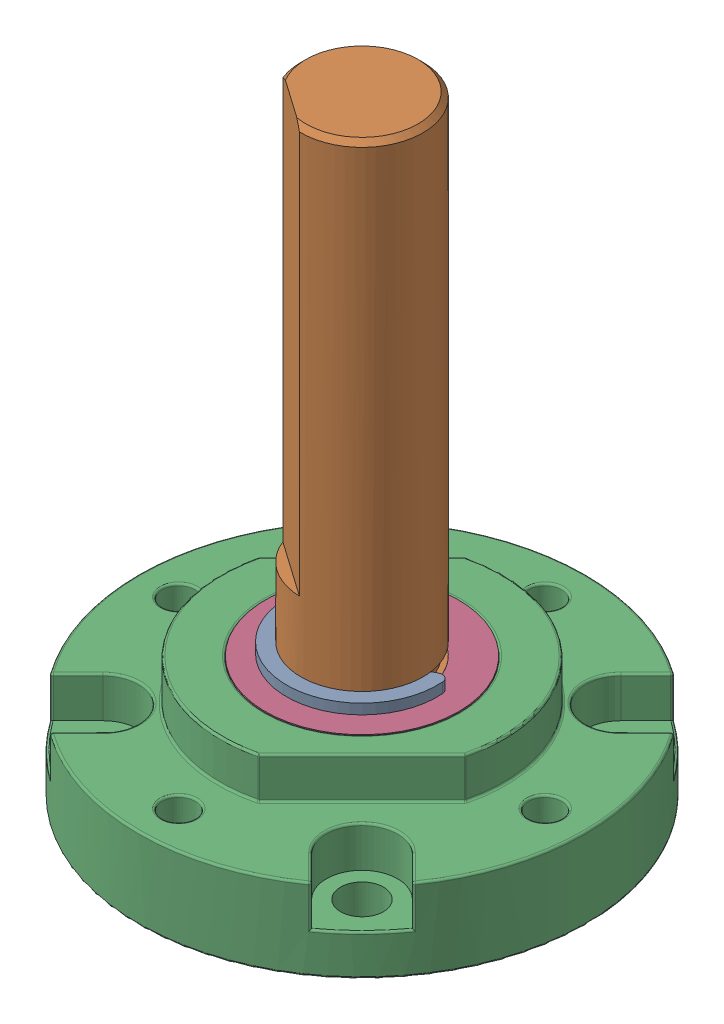
SolidWorks assembly Front Plate.stp, configuration Default. Lengths in mm.
Overall size (21.95 30.5 21.95).
5 component instances, 4 part files, 0 mates.
Components (placement in the parent):
- Shaft.stp-1: Shaft.stp [Default] x (-0.819152 0 -0.573576) z (0.573576 0 -0.819152) size (7.4 30.3 6.7)
  - Retaining Ring.stp-1: Retaining Ring.stp [Default] at (0 16.65 0) x (-1 0 0) z (0 -1 0) size (7.4 6.16 0.5)
  - Shaft-0.stp-1: Shaft-0.stp [Default] at origin size (6 30.3 6)
- Front Plate-1.stp-1: Front Plate-1.stp [Default] at origin size (21.95 6.5 21.95)
- Front Plate-2.stp-1: Front Plate-2.stp [Default] at origin size (9.5 6 9.5)
